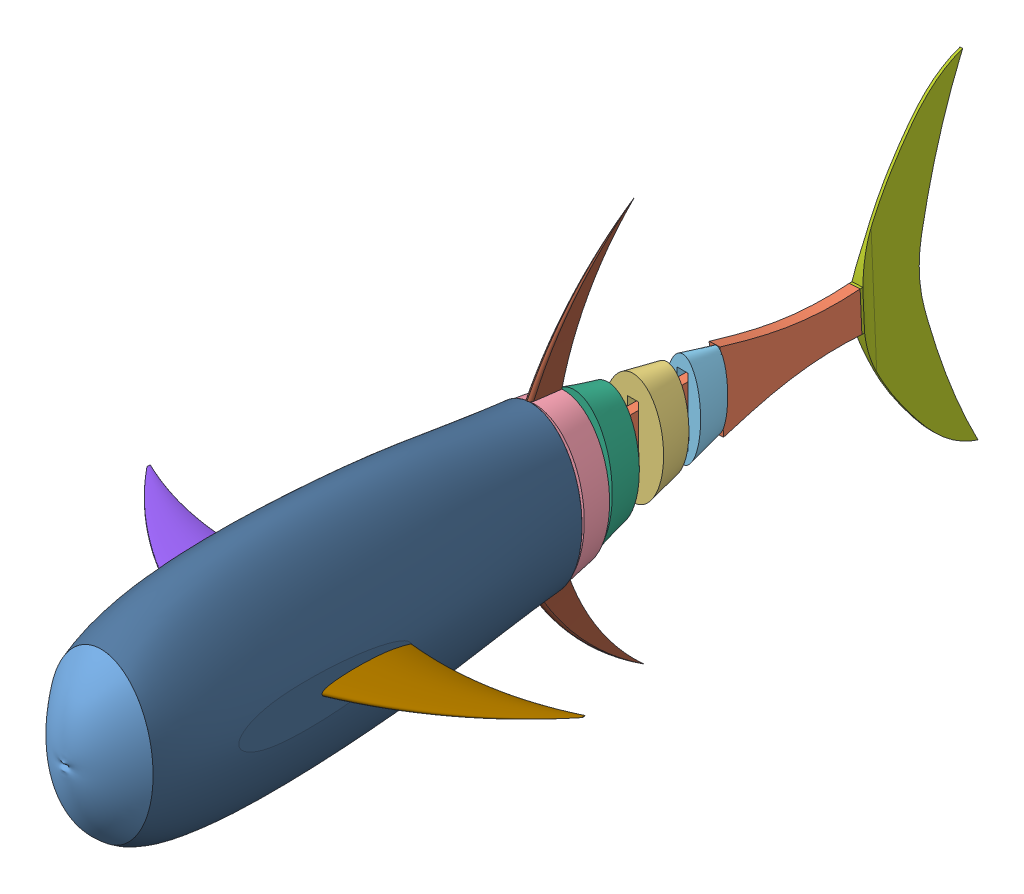
SolidWorks assembly Assem1, configuration Default. Lengths in mm.
Overall size (160.57 159.47 334.88).
12 component instances, 11 part files, 26 mates.
Components (placement in the parent):
- nose for assembly-1: nose for assembly [Default] at (155.0522 112.8767 151.9849) x (0.000473 0.000028 -1) z (1 -0.000016 0.000473) size (31.17 62.76 40.42)
- tailbackbone-2: tailbackbone [Default] at (153.0352 112.8355 123.366) x (0 0 -1) z (0.998946 0.045895 0) size (119.93 28.27 4)
- Vertebrate3-1: Vertebrate3 [Default] at (155.0852 112.8355 -56.8967) size (22.56 41.25 12.5)
- vertebrate1-2: vertebrate1 [Default] at (155.0581 112.877 -19.2651) x (0.99895 0.020505 -0.040974) z (0.040866 0.00566 0.999149) size (37.84 60.03 12.5)
- vertebrate4-4: vertebrate4 [Default] at (155.0852 112.8355 -75.2148) size (13.26 35.38 12.5)
- Vertebrate2-2: Vertebrate2 [Default] at (155.0352 112.8355 -35.1737) size (28.21 52.5 12.5)
- Caudal fin-4: Caudal fin [Default] at (155.0331 112.9273 -139.1143) x (0 0 1) z (0.998946 0.045895 0) size (41.88 122.5 8.81)
- pectorial fin right new-1: pectorial fin right new [Default] at (74.7881 113.3704 83.2042) x (0 0 -1) z (1 0 0) size (42.29 4.62 55.03)
- pectorial fin left new-1: pectorial fin left new [Default] at (125.3281 113.4899 83.1206) x (0 0 -1) z (1 0 0) size (42.29 4.62 55.03)
- headpart for assembly new-1: headpart for assembly new [Default] at (155.0581 112.877 151.9849) size (53.24 84.87 158.76)
- dorsal fin starting-6: dorsal fin starting [Default] at (153.8263 142.878 -19.0125) x (-0.000732 0.196713 0.980461) z (-0.999099 -0.041755 0.007632) size (32.63 50.77 2.53)
- dorsal fin starting-8: dorsal fin starting [Default] at (155.1073 82.8345 -18.733) x (-0.000742 -0.188798 0.982016) z (0.999923 0.01205 0.003073) size (32.63 50.77 2.53)
Mates (geometry in assembly coordinates):
- Coincident27: coincident: point of Vertebrate3-1
- Coincident40: coincident: unknown of tailbackbone-2; unknown of vertebrate1-2
- Coincident44: coincident: unknown of headpart jst for assembly-1
- Coincident46: coincident aligned: plane of headpart jst for assembly-1 through (156.2126 112.4074 139.5631) normal (-0.007259 0.002697 -0.99997); plane of nose for assembly-1 through (155.0581 112.877 139.4849) normal (0.000473 0.000028 -1)
- Coincident47: coincident: unknown of vertebrate4-4
- Parallel3: parallel anti-aligned: plane of pectorial fin right,top-1 through (169.4674 -87.3728 288.4012) normal (1 0 0); plane of pectorial fin left,top-1 through (150.6506 -97.4413 422.1991) normal (-1 0 0)
- Tangent2: tangent: face of vertebrate1-2; plane of ? through (153.0141 142.7915 -19.4353) normal (0.028242 -0.97975 0.198225)
- Coincident65: coincident: point of assembly; point of dorsal fin starting-5; point of assembly
- Tangent3: tangent: edge_curve of vertebrate1-2; plane of ? through (155.8142 82.9293 -19.1796) normal (-0.012413 0.981942 0.188775)
- Coincident66: coincident: point of assembly; point of dorsal fin starting-4; point of assembly
- Coincident67: coincident: unknown of Vertebrate2-2
- Parallel9: parallel anti-aligned: plane of tailbackbone-2 through (156.7033 120.1504 -139.1143) normal (0 0 -1); plane of Caudal fin-4 through (155.0331 112.9273 -139.1143) normal (0 0 1)
- Coincident80: coincident: point of tailbackbone-2; point of Caudal fin-4
- Parallel10: parallel anti-aligned: plane of pectorial fin right new-1 through (129.7881 113.3746 83.2042) normal (1 0 0); plane of pectorial fin left new-1 through (180.3281 113.4899 83.1206) normal (-1 0 0)
- Coincident83: coincident anti-aligned: plane of pectorial fin right new-1 through (129.7881 113.3746 83.2042) normal (1 0 0); plane of headpart for assembly new-1 through (129.7881 112.877 151.9849) normal (-1 0 0)
- Coincident84: coincident anti-aligned: plane of pectorial fin right new-1 through (129.7881 113.3746 83.2042) normal (1 0 0); plane of headpart for assembly new-1 through (129.7881 112.877 151.9849) normal (-1 0 0)
- Coincident85: coincident: curve of headpart-1; point of pectorial fin right new-1
- Coincident86: coincident anti-aligned: plane of pectorial fin left new-1 through (180.3281 113.4899 83.1206) normal (-1 0 0); plane of headpart for assembly new-1 through (180.3281 112.877 151.9849) normal (1 0 0)
- Coincident87: coincident: point of pectorial fin left new-1; curve of headpart-1
- Coincident95: coordinate: unknown of headpart for assembly new-1
- Coincident98: coincident: point of nose for assembly-1; point of headpart for assembly new-1
- Tangent12: tangent: plane of assembly; face of vertebrate1-2; plane of dorsal fin starting-6 through (153.0679 142.7594 -19.4397) normal (0.042441 -0.979572 0.196566)
- Coincident100: coincident: unknown of dorsal fin starting-6
- Tangent17: tangent: edge_curve of vertebrate1-2; plane of ? through (154.4435 81.7435 -55.2362) normal (0 1 0)
- Tangent18: tangent: plane of assembly; face of vertebrate1-2; plane of dorsal fin starting-8 through (155.867 82.9271 -19.1643) normal (-0.012413 0.981942 0.188775)
- Coincident104: coincident: unknown of dorsal fin starting-8
